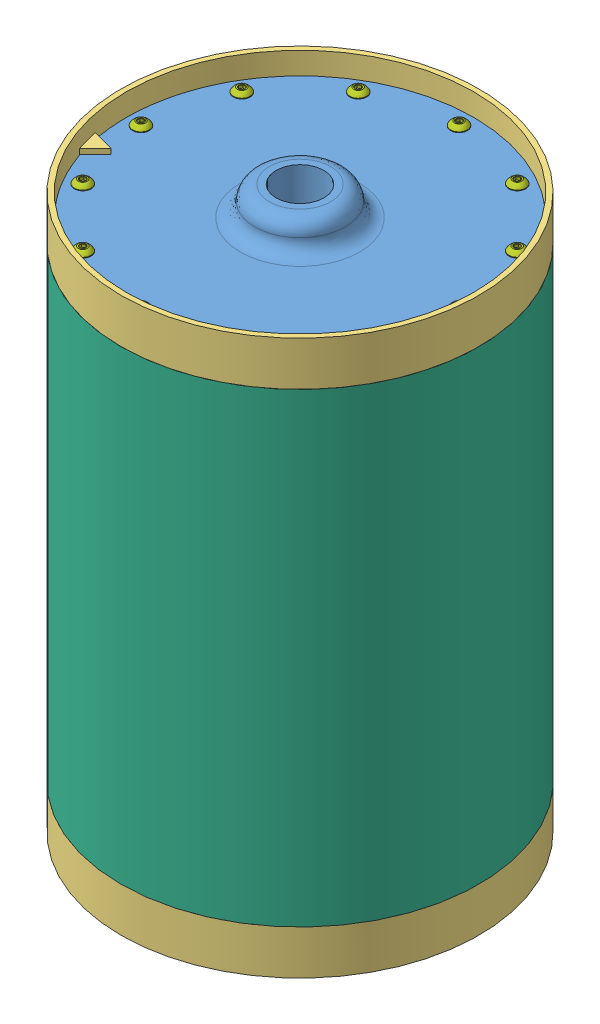
SolidWorks assembly Cryo Tank, configuration Default. Lengths in mm.
Overall size (102.62 162.69 102.62).
33 component instances, 8 part files, 26 mates.
Components (placement in the parent):
- 0301-C; End Cap-1: 0301-C; End Cap [Default] at origin size (99.57 28.96 99.57)
- Liner-1: Liner [Default] at (0 -4.7625 0) size (82.55 133.35 82.55)
- 0201-C; Main Ring-1: 0201-C; Main Ring [Default] at (0 -1.5875 0) size (102.51 25.4 102.51)
- 0201-C; Main Ring-2: 0201-C; Main Ring [Default] at (0 -141.2875 0) x (-1 0 0) z (0 0 1) size (102.51 25.4 102.51)
- 0301-C; End Cap-2: 0301-C; End Cap [Default] at (0 -142.875 0) x (-1 0 0) z (0 0 1) size (99.57 28.96 99.57)
- CF Inner Layer-1: CF Inner Layer [Default] at (0 64.2407 0) size (89.41 133.35 89.41)
- Honeycomb Core-1: Honeycomb Core [Default] at (0 -50.3801 0) size (102.11 133.35 102.11)
- CF Outer Layer-1: CF Outer Layer [Default] at (0 15.1434 0) size (102.62 133.35 102.62)
- 92949A325_18-8 SS BUTTON-HEAD SOCKET CAP SCREW-1: 92949A325_18-8 SS BUTTON-HEAD SOCKET CAP SCREW [92949A325] at (45.5549 2.9083 0) x (1 0 0) z (0 1 0) size (4.78 4.78 7.95)
- 92949A325_18-8 SS BUTTON-HEAD SOCKET CAP SCREW-2: 92949A325_18-8 SS BUTTON-HEAD SOCKET CAP SCREW [92949A325] at (45.5549 -145.7833 0) x (1 0 0) z (0 -1 0) size (4.78 4.78 7.95)
- 92949A325_18-8 SS BUTTON-HEAD SOCKET CAP SCREW-3: 92949A325_18-8 SS BUTTON-HEAD SOCKET CAP SCREW [92949A325] at (39.4517 -145.7833 -22.7775) x (0.866025 0 -0.5) z (0 -1 0) size (4.78 4.78 7.95)
- 92949A325_18-8 SS BUTTON-HEAD SOCKET CAP SCREW-4: 92949A325_18-8 SS BUTTON-HEAD SOCKET CAP SCREW [92949A325] at (22.7775 -145.7833 -39.4517) x (0.5 0 -0.866025) z (0 -1 0) size (4.78 4.78 7.95)
- 92949A325_18-8 SS BUTTON-HEAD SOCKET CAP SCREW-5: 92949A325_18-8 SS BUTTON-HEAD SOCKET CAP SCREW [92949A325] at (0 -145.7833 -45.5549) x (0 0 -1) z (0 -1 0) size (4.78 4.78 7.95)
- 92949A325_18-8 SS BUTTON-HEAD SOCKET CAP SCREW-6: 92949A325_18-8 SS BUTTON-HEAD SOCKET CAP SCREW [92949A325] at (-22.7775 -145.7833 -39.4517) x (-0.5 0 -0.866025) z (0 -1 0) size (4.78 4.78 7.95)
- 92949A325_18-8 SS BUTTON-HEAD SOCKET CAP SCREW-7: 92949A325_18-8 SS BUTTON-HEAD SOCKET CAP SCREW [92949A325] at (-39.4517 -145.7833 -22.7775) x (-0.866025 0 -0.5) z (0 -1 0) size (4.78 4.78 7.95)
- 92949A325_18-8 SS BUTTON-HEAD SOCKET CAP SCREW-8: 92949A325_18-8 SS BUTTON-HEAD SOCKET CAP SCREW [92949A325] at (-45.5549 -145.7833 0) x (-1 0 0) z (0 -1 0) size (4.78 4.78 7.95)
- 92949A325_18-8 SS BUTTON-HEAD SOCKET CAP SCREW-9: 92949A325_18-8 SS BUTTON-HEAD SOCKET CAP SCREW [92949A325] at (-39.4517 -145.7833 22.7775) x (-0.866025 0 0.5) z (0 -1 0) size (4.78 4.78 7.95)
- 92949A325_18-8 SS BUTTON-HEAD SOCKET CAP SCREW-10: 92949A325_18-8 SS BUTTON-HEAD SOCKET CAP SCREW [92949A325] at (-22.7775 -145.7833 39.4517) x (-0.5 0 0.866025) z (0 -1 0) size (4.78 4.78 7.95)
- 92949A325_18-8 SS BUTTON-HEAD SOCKET CAP SCREW-11: 92949A325_18-8 SS BUTTON-HEAD SOCKET CAP SCREW [92949A325] at (0 -145.7833 45.5549) x (0 0 1) z (0 -1 0) size (4.78 4.78 7.95)
- 92949A325_18-8 SS BUTTON-HEAD SOCKET CAP SCREW-12: 92949A325_18-8 SS BUTTON-HEAD SOCKET CAP SCREW [92949A325] at (22.7775 -145.7833 39.4517) x (0.5 0 0.866025) z (0 -1 0) size (4.78 4.78 7.95)
- 92949A325_18-8 SS BUTTON-HEAD SOCKET CAP SCREW-13: 92949A325_18-8 SS BUTTON-HEAD SOCKET CAP SCREW [92949A325] at (39.4517 -145.7833 22.7775) x (0.866025 0 0.5) z (0 -1 0) size (4.78 4.78 7.95)
- 92949A325_18-8 SS BUTTON-HEAD SOCKET CAP SCREW-14: 92949A325_18-8 SS BUTTON-HEAD SOCKET CAP SCREW [92949A325] at (39.4517 2.9083 -22.7775) x (0.866025 0 -0.5) z (0 1 0) size (4.78 4.78 7.95)
- 92949A325_18-8 SS BUTTON-HEAD SOCKET CAP SCREW-15: 92949A325_18-8 SS BUTTON-HEAD SOCKET CAP SCREW [92949A325] at (22.7775 2.9083 -39.4517) x (0.5 0 -0.866025) z (0 1 0) size (4.78 4.78 7.95)
- 92949A325_18-8 SS BUTTON-HEAD SOCKET CAP SCREW-16: 92949A325_18-8 SS BUTTON-HEAD SOCKET CAP SCREW [92949A325] at (0 2.9083 -45.5549) x (0 0 -1) z (0 1 0) size (4.78 4.78 7.95)
- 92949A325_18-8 SS BUTTON-HEAD SOCKET CAP SCREW-17: 92949A325_18-8 SS BUTTON-HEAD SOCKET CAP SCREW [92949A325] at (-22.7775 2.9083 -39.4517) x (-0.5 0 -0.866025) z (0 1 0) size (4.78 4.78 7.95)
- 92949A325_18-8 SS BUTTON-HEAD SOCKET CAP SCREW-18: 92949A325_18-8 SS BUTTON-HEAD SOCKET CAP SCREW [92949A325] at (-39.4517 2.9083 -22.7775) x (-0.866025 0 -0.5) z (0 1 0) size (4.78 4.78 7.95)
- 92949A325_18-8 SS BUTTON-HEAD SOCKET CAP SCREW-19: 92949A325_18-8 SS BUTTON-HEAD SOCKET CAP SCREW [92949A325] at (-45.5549 2.9083 0) x (-1 0 0) z (0 1 0) size (4.78 4.78 7.95)
- 92949A325_18-8 SS BUTTON-HEAD SOCKET CAP SCREW-20: 92949A325_18-8 SS BUTTON-HEAD SOCKET CAP SCREW [92949A325] at (-39.4517 2.9083 22.7775) x (-0.866025 0 0.5) z (0 1 0) size (4.78 4.78 7.95)
- 92949A325_18-8 SS BUTTON-HEAD SOCKET CAP SCREW-21: 92949A325_18-8 SS BUTTON-HEAD SOCKET CAP SCREW [92949A325] at (-22.7775 2.9083 39.4517) x (-0.5 0 0.866025) z (0 1 0) size (4.78 4.78 7.95)
- 92949A325_18-8 SS BUTTON-HEAD SOCKET CAP SCREW-22: 92949A325_18-8 SS BUTTON-HEAD SOCKET CAP SCREW [92949A325] at (0 2.9083 45.5549) x (0 0 1) z (0 1 0) size (4.78 4.78 7.95)
- 92949A325_18-8 SS BUTTON-HEAD SOCKET CAP SCREW-23: 92949A325_18-8 SS BUTTON-HEAD SOCKET CAP SCREW [92949A325] at (22.7775 2.9083 39.4517) x (0.5 0 0.866025) z (0 1 0) size (4.78 4.78 7.95)
- 92949A325_18-8 SS BUTTON-HEAD SOCKET CAP SCREW-24: 92949A325_18-8 SS BUTTON-HEAD SOCKET CAP SCREW [92949A325] at (39.4517 2.9083 22.7775) x (0.866025 0 0.5) z (0 1 0) size (4.78 4.78 7.95)
- Inner Honeycomb Layer-1: Inner Honeycomb Layer [Default] at (0 -54.4416 0) size (88.8 107.95 88.8)
Mates (geometry in assembly coordinates):
- Coincident13: coincident: point of Liner-1; point of assembly
- Coincident14: coincident aligned: plane of Liner-1 through (0 -4.7625 0) normal (0 0 1); plane of assembly through (0 0 0) normal (0 0 1)
- Coincident15: coincident aligned: plane of 0301-C; End Cap-1 through (0 0 0) normal (0 0 1); plane of assembly through (0 0 0) normal (0 0 1)
- Coincident16: coordinate: point of 0301-C; End Cap-1; point of assembly
- Coincident20: coincident anti-aligned: line of 0201-C; Main Ring-1 through (110 0 53.4125) axis (0 0 -1); line of assembly
- Coincident21: coincident aligned: plane of 0201-C; Main Ring-1 through (0 -1.5875 0) normal (0 0 1); plane of assembly through (0 0 0) normal (0 0 1)
- Coincident22: coincident: point of 0201-C; Main Ring-1; point of assembly
- Coincident26: coincident aligned: line of 0301-C; End Cap-2 through (110 0 -197.875) axis (0 0 1); line of assembly
- Coincident27: coincident aligned: plane of 0301-C; End Cap-2 through (0 -142.875 0) normal (0 0 1); plane of assembly through (0 0 0) normal (0 0 1)
- Coincident28: coincident: point of 0301-C; End Cap-2; point of assembly
- Coincident29: coincident aligned: line of 0201-C; Main Ring-2 through (110 0 -196.2875) axis (0 0 1); line of assembly
- Coincident30: coincident aligned: plane of 0201-C; Main Ring-2 through (0 -141.2875 0) normal (0 0 1); plane of assembly through (0 0 0) normal (0 0 1)
- Coincident31: coincident: point of 0201-C; Main Ring-2; point of assembly
- Coincident35: coincident aligned: line of 0201-C; Main Ring-1 through (110 0 53.4125) axis (0 0 -1); line of CF Inner Layer-1 through (110 0 119.2407) axis (0 0 -1)
- Coincident36: coincident aligned: plane of CF Inner Layer-1 through (0 64.2407 0) normal (0 0 1); plane of assembly through (0 0 0) normal (0 0 1)
- Coincident37: coincident aligned: line of CF Inner Layer-1 through (110 0 119.2407) axis (0 0 -1); line of Honeycomb Core-1 through (110 0 4.6199) axis (0 0 -1)
- Coincident38: coincident aligned: plane of Honeycomb Core-1 through (0 -50.3801 0) normal (0 0 1); plane of assembly through (0 0 0) normal (0 0 1)
- Coincident39: coincident aligned: line of CF Inner Layer-1 through (110 0 119.2407) axis (0 0 -1); line of CF Outer Layer-1 through (110 0 70.1434) axis (0 0 -1)
- Coincident40: coincident aligned: plane of CF Outer Layer-1 through (0 15.1434 0) normal (0 0 1); plane of assembly through (0 0 0) normal (0 0 1)
- Coincident44: coincident anti-aligned: line of Inner Honeycomb Layer-1 through (110 0 0.5584) axis (0 0 -1); line of assembly
- Coincident45: coincident anti-aligned: plane of 0301-C; End Cap-1 through (-49.784 1.5875 0) normal (0 1 0); plane of 92949A325_18-8 SS BUTTON-HEAD SOCKET CAP SCREW-19 through (-45.5549 1.5875 -2.3876) normal (0 -1 0)
- Concentric1: concentric: point of 0301-C; End Cap-1; cylinder of 92949A325_18-8 SS BUTTON-HEAD SOCKET CAP SCREW-19 through (-45.5549 2.9083 0) axis (0 1 0) radius 2.3876
- Coincident47: coincident anti-aligned: plane of 92949A325_18-8 SS BUTTON-HEAD SOCKET CAP SCREW-1 through (45.5549 2.9083 0) normal (0 0 -1); plane of assembly through (0 0 0) normal (0 0 1)
- Coincident48: coincident anti-aligned: plane of 0301-C; End Cap-2 through (49.784 -144.4625 0) normal (0 -1 0); plane of 92949A325_18-8 SS BUTTON-HEAD SOCKET CAP SCREW-8 through (-45.5549 -144.4625 2.3876) normal (0 1 0)
- Concentric2: concentric aligned: cylinder of 0301-C; End Cap-2 through (-45.5549 -144.4625 0) axis (0 -1 0) radius 1.3526; cylinder of 92949A325_18-8 SS BUTTON-HEAD SOCKET CAP SCREW-8 through (-45.5549 -145.7833 0) axis (0 -1 0) radius 2.3876
- Coincident49: coincident aligned: plane of 92949A325_18-8 SS BUTTON-HEAD SOCKET CAP SCREW-2 through (45.5549 -145.7833 0) normal (0 0 1); plane of assembly through (0 0 0) normal (0 0 1)
